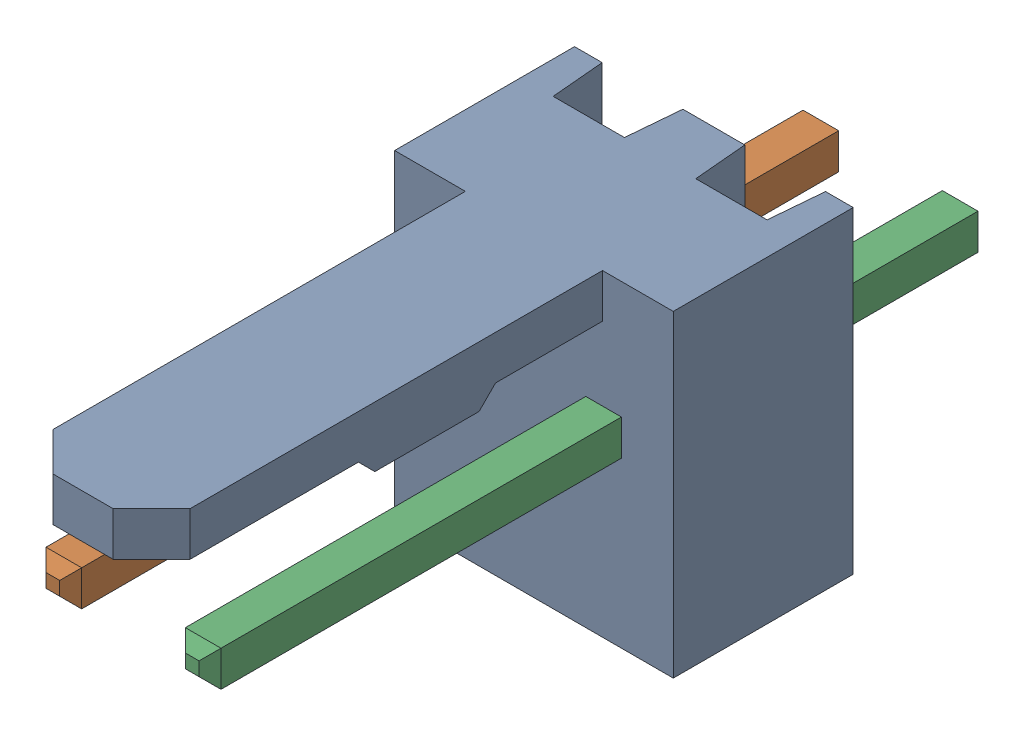
SolidWorks assembly Molex PCB 2 pin v2 (3), configuration Default. Lengths in mm.
Overall size (5.08 5.79 14.92).
3 component instances, 2 part files, 0 mates.
Components (placement in the parent):
- BASE9710016-1: BASE9710016 [Default] at (2.54 2.895 -8.22) size (5.08 5.79 11.5)
- PINO9710016-1: PINO9710016 [Default] at (1.27 3.325 -0.72) size (0.65 0.65 14.2)
- PINO9710016-2: PINO9710016 [Default] at (3.81 3.325 -0.72) size (0.65 0.65 14.2)
